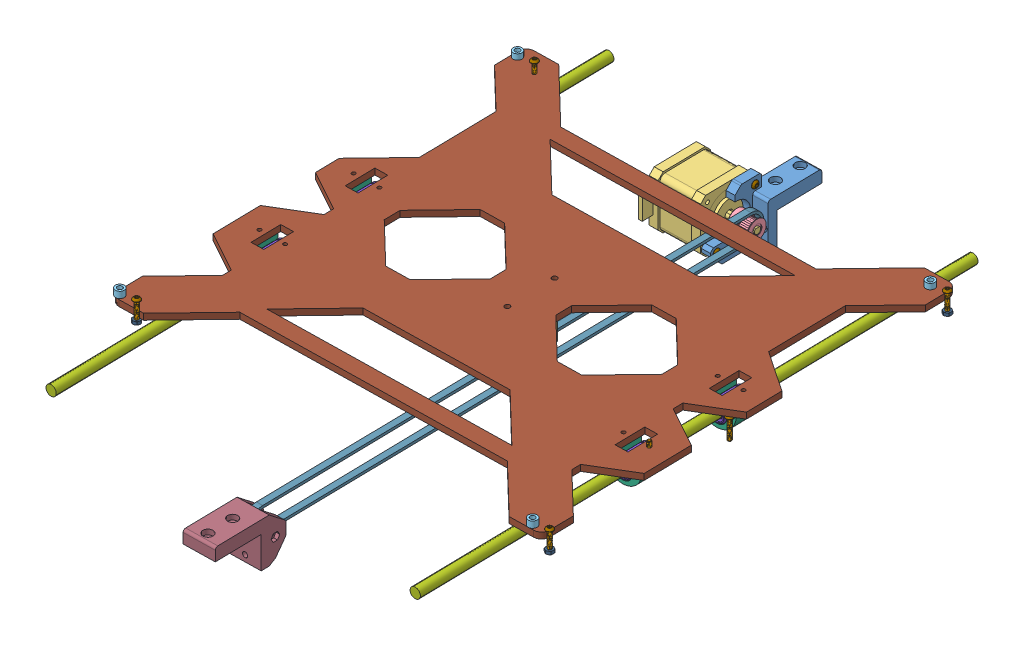
SolidWorks assembly Y Assembly, configuration Default. Lengths in mm.
Overall size (352.33 81 500.19).
42 component instances, 16 part files, 59 mates.
Components (placement in the parent):
- PrintBed_328x328-1: PrintBed_328x328 [Default] at (148.0124 43.9926 305.9077) x (0.999825 0 -0.018712) z (0.018712 0 0.999825) size (328 2 340) (hidden)
- y axis motor holder-1: y axis motor holder [Default] at (-4.3973 -9.082 94.7066) x (0 1 0) z (0.999825 0 -0.018712) size (46.75 77.5 19)
- 624U pillow-1: 624U pillow [Standard] at (74.1469 -91.082 589.2534) x (0 1 0) z (0.018712 0 0.999825) size (13 4 13)
- 40-42 motor-1: 40-42 motor [Standard] at (-45.9053 -85.582 96.0835) x (0 1 0) z (-0.018712 0 -0.999825) size (42 64 50.7)
- 2GT-pulley-2: 2GT-pulley [Standard] at (-58.242 121.3888 274.0832) x (0.999825 0 -0.018712) z (0.018712 0 0.999825) size (16 15 15)
- 5mm Bed Spacer-1: 5mm Bed Spacer [Default] at (-134.2258 34.9926 494.9836) size (7 5 7)
- 5mm Bed Spacer-2: 5mm Bed Spacer [Default] at (186.7203 34.9926 489.0988) size (7 5 7)
- 5mm Bed Spacer-3: 5mm Bed Spacer [Default] at (180.5919 34.398 168.1573) size (7 5 7)
- 5mm Bed Spacer-4: 5mm Bed Spacer [Default] at (-140.2301 34.398 174.1616) size (7 5 7)
- HeatBed 300mm-1: HeatBed 300mm [Default] at (26.2199 39.9926 264.6988) x (0.999825 0 -0.018712) z (0.018712 0 0.999825) size (327 4 327) (hidden)
- Bed Holder-3: Bed Holder [Default] at (-121.7577 30.1666 403.8738) x (0.018712 0 0.999825) z (0.999825 0 -0.018712) size (22 20 30)
- Bed Holder-4: Bed Holder [Default] at (159.7692 30.1666 322.5141) x (0.018712 0 0.999825) z (0.999825 0 -0.018712) size (22 20 30)
- Bed Holder-5: Bed Holder [Default] at (160.7796 30.1666 376.5016) x (-0.018712 0 -0.999825) z (-0.999825 0 0.018712) size (22 20 30)
- Bed Holder-6: Bed Holder [Default] at (-123.593 30.1666 305.8134) x (-0.018712 0 -0.999825) z (-0.999825 0 0.018712) size (22 20 30)
- BedSlider-1: BedSlider [Default] at (160.3516 26.2711 115.9371) x (0.404254 0.914616 -0.007566) z (0.018712 0 0.999825) size (8 8 450)
- BedSlider-2: BedSlider [Default] at (-126.0037 27.7452 121.2964) x (-0.108153 0.994132 0.002024) z (0.018712 0 0.999825) size (8 8 450)
- lm8uu-1: lm8uu [Default] at (159.5633 20.6666 311.516) x (0.999825 0 -0.018712) z (0.018712 0 0.999825) size (15 15 24)
- lm8uu-2: lm8uu [Default] at (160.9854 20.6666 387.4997) x (0.999825 0 -0.018712) z (0.018712 0 0.999825) size (15 15 24)
- lm8uu-3: lm8uu [Default] at (-121.9636 20.6666 392.8757) x (0.999825 0 -0.018712) z (0.018712 0 0.999825) size (15 15 24)
- lm8uu-4: lm8uu [Default] at (-123.3871 20.6666 316.8115) x (0.999825 0 -0.018712) z (0.018712 0 0.999825) size (15 15 24)
- M3X16MM-1: M3X16MM [92095A184] at (190.5681 45.048 170.847) x (0.585178 0 0.810905) z (0 1 0) size (5.7 5.7 18)
- M3X16MM-2: M3X16MM [92095A184] at (-130.3757 45.048 176.8536) x (0.988184 0 0.153271) z (0 1 0) size (5.7 5.7 18)
- M3X16MM-3: M3X16MM [92095A184] at (-124.3691 45.048 497.7974) x (0.998383 0 0.056849) z (0 1 0) size (5.7 5.7 18)
- M3X16MM-4: M3X16MM [92095A184] at (196.5747 45.048 491.7908) x (0.969741 0 0.244134) z (0 1 0) size (5.7 5.7 18)
- M3-1: M3 [90591A250] at (-130.3757 17.3906 176.8536) x (0.962335 0 -0.271866) z (0 1 0) size (5.5 6.35 2.78)
- M3-2: M3 [90591A250] at (190.5681 28.9666 170.847) x (1 0 0) z (0 1 0) size (5.5 6.35 2.78)
- M3-3: M3 [90591A250] at (196.5747 28.9666 491.7908) x (1 0 0) z (0 1 0) size (5.5 6.35 2.78)
- M3-4: M3 [90591A250] at (-124.3691 28.9666 497.7974) x (0.977813 0 0.209477) z (0 -1 0) size (5.5 6.35 2.78)
- M3X16MM-5: M3X16MM [92095A184] at (170.9836 21.7666 387.3126) x (-0.990608 0 0.136731) z (0 -1 0) size (5.7 5.7 18)
- M3X16MM-6: M3X16MM [92095A184] at (150.939 25.0666 399.5855) x (-0.757878 0 0.652397) z (0 1 0) size (5.7 5.7 18)
- M3X16MM-7: M3X16MM [92095A184] at (150.939 25.0666 323.5885) x (-0.527844 0 0.849341) z (0 1 0) size (5.7 5.7 18)
- M3X16MM-8: M3X16MM [92095A184] at (170.939 25.0666 323.5885) x (-0.850892 0 0.525341) z (0 1 0) size (5.7 5.7 18)
- M3X16MM-9: M3X16MM [92095A184] at (-127.261 25.0666 399.5855) x (-0.32634 0 -0.945252) z (0 1 0) size (5.7 5.7 18)
- M3X16MM-10: M3X16MM [92095A184] at (-107.261 25.0666 399.5855) x (-0.992075 0 0.125643) z (0 1 0) size (5.7 5.7 18)
- M3X16MM-11: M3X16MM [92095A184] at (-127.261 25.0666 323.5885) x (-0.951434 0 -0.307853) z (0 1 0) size (5.7 5.7 18)
- M3X16MM-12: M3X16MM [92095A184] at (-107.261 25.871 323.5885) x (-0.671818 0 -0.740717) z (0 1 0) size (5.7 5.7 18)
- M3X16MM-13: M3X16MM [92095A184] at (5.6078 -25.582 167.032) x (-0.018712 0 -0.999825) z (0.999825 0 -0.018712) size (5.7 5.7 18)
- M3X16MM-14: M3X16MM [92095A184] at (5.0277 5.418 136.0374) x (-0.018712 0 -0.999825) z (0.999825 0 -0.018712) size (5.7 5.7 18)
- flatbed-2: flatbed [Default] at (144.4975 32.5796 357.2347) x (0.999825 0 -0.018712) z (0 -1 0) size (335 335 4.83)
- y belt holder-1: y belt holder [Default] at (10.4795 30.1666 328.4691) x (0.999825 0 -0.018712) z (0 -1 0) size (14 52 33.5)
- Y axis Idler Holder-1: Y axis Idler Holder [Default] at (21.7058 0.918 594.3056) x (0.018712 0 0.999825) z (0 -1 0) size (56.89 25 35)
- belt-4: belt [Default] at (16.5258 -7.7421 183.9241) x (0.01871 0.016655 0.999686) z (-0.999825 0 0.018712) size (414.43 26.57 5)
Mates (geometry in assembly coordinates):
- Concentric1: concentric aligned: cylinder of 40-42 motor-1 through (20.665 -10.082 151.2475) axis (-0.999825 0 0.018712) radius 2.5; cylinder of 2GT-pulley-2 through (4.6678 -10.082 151.5469) axis (-0.999825 0 0.018712) radius 2.5
- Distance1: distance = 5.5 mm anti-aligned: plane of 2GT-pulley-2 through (4.1679 -10.082 151.5562) normal (-0.999825 0 0.018712); plane of 40-42 motor-1 through (-1.3311 -10.082 151.6592) normal (0.999825 0 -0.018712)
- Coincident37: coincident anti-aligned: plane of PrintBed_328x328-1 through (148.0124 43.9926 305.9077) normal (0 -1 0); plane of HeatBed 300mm-1 through (26.2199 43.9926 264.6988) normal (0 1 0)
- Coincident38: coincident aligned: plane of PrintBed_328x328-1 through (-152.5991 45.9926 169.1586) normal (-0.018712 0 -0.999825); plane of HeatBed 300mm-1 through (-151.5993 43.9926 169.1399) normal (-0.018712 0 -0.999825)
- Coincident39: coincident aligned: plane of PrintBed_328x328-1 through (175.3434 45.9926 163.021) normal (0.999825 0 -0.018712); plane of HeatBed 300mm-1 through (175.3434 43.9926 163.021) normal (0.999825 0 -0.018712)
- Concentric7: concentric aligned: cylinder of Bed Holder-3 through (-121.7016 20.6666 406.8733) axis (-0.018712 0 -0.999825) radius 7.735; cylinder of BedSlider-2 through (-118.6254 20.6666 571.2371) axis (-0.018712 0 -0.999825) radius 4
- Concentric8: concentric anti-aligned: cylinder of Bed Holder-6 through (-123.6491 20.6666 302.814) axis (0.018712 0 0.999825) radius 7.735; cylinder of BedSlider-2 through (-118.6254 20.6666 571.2371) axis (-0.018712 0 -0.999825) radius 4
- Concentric10: concentric anti-aligned: cylinder of Bed Holder-5 through (160.7234 20.6666 373.5021) axis (0.018712 0 0.999825) radius 7.735; cylinder of BedSlider-1 through (164.325 20.6666 565.9415) axis (-0.018712 0 -0.999825) radius 4
- Concentric11: concentric aligned: cylinder of Bed Holder-4 through (159.8253 20.6666 325.5135) axis (-0.018712 0 -0.999825) radius 7.735; cylinder of BedSlider-1 through (164.325 20.6666 565.9415) axis (-0.018712 0 -0.999825) radius 4
- Concentric16: concentric aligned: cylinder of Bed Holder-3 through (-121.7016 20.6666 406.8733) axis (-0.018712 0 -0.999825) radius 7.735; cylinder of lm8uu-3 through (-121.739 20.6666 404.8736) axis (-0.018712 0 -0.999825) radius 7.5
- Distance18: distance = 1 mm aligned: plane of lm8uu-3 through (-121.739 20.6666 404.8736) normal (0.018712 0 0.999825); plane of Bed Holder-3 through (-136.7551 10.1666 404.1545) normal (0.018712 0 0.999825)
- Concentric17: concentric anti-aligned: cylinder of Bed Holder-6 through (-123.6491 20.6666 302.814) axis (0.018712 0 0.999825) radius 7.735; cylinder of lm8uu-4 through (-123.1626 20.6666 328.8094) axis (-0.018712 0 -0.999825) radius 7.5
- Distance19: distance = 1 mm aligned: plane of lm8uu-4 through (-123.1626 20.6666 328.8094) normal (0.018712 0 0.999825); plane of Bed Holder-6 through (-108.1839 10.1666 327.5289) normal (0.018712 0 0.999825)
- Concentric18: concentric aligned: cylinder of Bed Holder-4 through (159.8253 20.6666 325.5135) axis (-0.018712 0 -0.999825) radius 7.735; cylinder of lm8uu-1 through (159.7879 20.6666 323.5139) axis (-0.018712 0 -0.999825) radius 7.5
- Distance20: distance = 1 mm aligned: plane of lm8uu-1 through (159.3388 20.6666 299.5181) normal (-0.018712 0 -0.999825); plane of Bed Holder-4 through (144.3601 10.1666 300.7986) normal (-0.018712 0 -0.999825)
- Concentric19: concentric anti-aligned: cylinder of Bed Holder-5 through (160.7234 20.6666 373.5021) axis (0.018712 0 0.999825) radius 7.735; cylinder of lm8uu-2 through (161.2099 20.6666 399.4976) axis (-0.018712 0 -0.999825) radius 7.5
- Distance21: distance = 1 mm aligned: plane of lm8uu-2 through (160.7608 20.6666 375.5018) normal (-0.018712 0 -0.999825); plane of Bed Holder-5 through (175.7769 10.1666 376.2209) normal (-0.018712 0 -0.999825)
- Coincident66: coincident aligned: plane of BedSlider-1 through (155.9045 20.6666 116.0203) normal (-0.018712 0 -0.999825); plane of BedSlider-2 through (-127.0459 20.6666 121.3159) normal (-0.018712 0 -0.999825)
- Coincident67: coincident anti-aligned: plane of y axis motor holder-1 through (-4.3973 -9.082 94.7066) normal (-0.999825 0 0.018712); plane of 40-42 motor-1 through (-3.3308 -10.082 151.6966) normal (0.999825 0 -0.018712)
- Concentric30: concentric anti-aligned: circle of M3X16MM-2; circle of M3-1
- Concentric31: concentric anti-aligned: cylinder of M3X16MM-3 through (-124.3691 45.048 497.7974) axis (0 1 0) radius 2.85; circle of M3-4
- Concentric33: concentric anti-aligned: circle of M3X16MM-4; circle of M3-3
- Concentric34: concentric aligned: circle of M3X16MM-1; circle of M3-2
- Concentric36: concentric anti-aligned: circle of Bed Holder-5; circle of M3X16MM-5
- Concentric44: concentric anti-aligned: cylinder of y axis motor holder-1 through (15.3759 5.418 135.8438) axis (-0.999825 0 0.018712) radius 1.625; cylinder of M3X16MM-14 through (5.0277 5.418 136.0374) axis (0.999825 0 -0.018712) radius 2.85
- Concentric45: concentric anti-aligned: cylinder of y axis motor holder-1 through (15.956 -25.582 166.8383) axis (-0.999825 0 0.018712) radius 1.625; circle of M3X16MM-13
- Coincident92: coincident anti-aligned: plane of y axis motor holder-1 through (3.6593 -10.0412 151.0983) normal (0.999825 0 -0.018712); plane of M3X16MM-13 through (3.9581 -28.432 167.0629) normal (-0.999825 0 0.018712)
- Coincident93: coincident anti-aligned: plane of y axis motor holder-1 through (3.6593 -10.0412 151.0983) normal (0.999825 0 -0.018712); plane of M3X16MM-14 through (3.378 2.568 136.0683) normal (-0.999825 0 0.018712)
- Concentric47: concentric aligned: cylinder of 40-42 motor-1 through (-8.0398 -25.582 167.2874) axis (0.999825 0 -0.018712) radius 1.5; circle of M3X16MM-13
- Concentric48: concentric aligned: cylinder of 40-42 motor-1 through (-8.6199 5.418 136.2929) axis (0.999825 0 -0.018712) radius 1.5; circle of M3X16MM-14
- Coincident97: coincident anti-aligned: plane of 5mm Bed Spacer-2 through (178.4067 34.9926 487.0204) normal (0 -1 0); plane of flatbed-2 through (144.4975 34.9926 357.2347) normal (0 1 0)
- Concentric50: concentric anti-aligned: cylinder of 5mm Bed Spacer-3 through (172.2783 39.398 166.0789) axis (0 -1 0) radius 2; cylinder of flatbed-2 through (172.2783 30.1666 166.0789) axis (0 1 0) radius 1.4605
- Concentric51: concentric anti-aligned: cylinder of 5mm Bed Spacer-1 through (-142.5394 39.9926 492.9052) axis (0 -1 0) radius 2; cylinder of flatbed-2 through (-142.5394 30.1666 492.9052) axis (0 1 0) radius 1.4605
- Coincident98: coincident anti-aligned: circle of 5mm Bed Spacer-1; plane of HeatBed 300mm-1 through (26.2199 39.9926 264.6988) normal (0 -1 0)
- Coincident99: coincident anti-aligned: plane of 5mm Bed Spacer-1 through (-142.5394 34.9926 492.9052) normal (0 -1 0); plane of flatbed-2 through (144.4975 34.9926 357.2347) normal (0 1 0)
- Concentric52: concentric aligned: cylinder of 5mm Bed Spacer-4 through (-148.5437 39.398 172.0832) axis (0 -1 0) radius 2; circle of flatbed-2
- Coincident101: coincident anti-aligned: plane of M3-2 through (187.8181 30.1666 169.2593) normal (0 1 0); plane of flatbed-2 through (144.4975 30.1666 357.2347) normal (0 -1 0)
- Coincident102: coincident anti-aligned: plane of M3-3 through (193.8247 30.1666 490.2031) normal (0 1 0); plane of flatbed-2 through (144.4975 30.1666 357.2347) normal (0 -1 0)
- Coincident103: coincident anti-aligned: plane of M3-4 through (-127.3907 30.1666 498.7738) normal (0 1 0); plane of flatbed-2 through (144.4975 30.1666 357.2347) normal (0 -1 0)
- Coincident104: coincident anti-aligned: plane of flatbed-2 through (144.4975 30.1666 357.2347) normal (0 -1 0); plane of y belt holder-1 through (10.966 30.1666 354.4646) normal (0 1 0)
- Concentric53: concentric anti-aligned: cylinder of flatbed-2 through (17.9966 30.1666 309.2751) axis (0 1 0) radius 2; cylinder of y belt holder-1 through (17.9966 19.1666 309.2751) axis (0 -1 0) radius 3.5
- Concentric54: concentric anti-aligned: cylinder of flatbed-2 through (18.7095 30.1666 347.3684) axis (0 1 0) radius 2; cylinder of y belt holder-1 through (18.7095 19.1666 347.3684) axis (0 -1 0) radius 3.75
- Coincident108: coincident anti-aligned: plane of Bed Holder-6 through (-123.593 30.1666 305.8134) normal (0 1 0); plane of flatbed-2 through (144.4975 30.1666 357.2347) normal (0 -1 0)
- Concentric56: concentric anti-aligned: circle of Bed Holder-5; circle of flatbed-2
- Concentric57: concentric aligned: circle of Bed Holder-4; circle of flatbed-2
- Concentric66: concentric anti-aligned: circle of HeatBed 300mm-1; circle of flatbed-2
- Concentric67: concentric aligned: circle of 5mm Bed Spacer-2; circle of HeatBed 300mm-1
- Distance22: distance = 3 mm anti-aligned: plane of 624U pillow-1 through (22.931 -7.582 552.8871) normal (0.999825 0 -0.018712); plane of Y axis Idler Holder-1 through (25.8909 0.918 550.7197) normal (-0.999825 0 0.018712)
- Concentric68: concentric aligned: circle of 624U pillow-1; circle of Y axis Idler Holder-1
- Distance25: distance = 500 mm anti-aligned: plane of Y axis Idler Holder-1 through (9.208 -9.082 594.5395) normal (0.018712 0 0.999825); plane of y axis motor holder-1 through (14.5993 -9.082 94.351) normal (-0.018712 0 -0.999825)
- Distance37: distance = 0.5 mm aligned: plane of 624U pillow-1 through (22.931 -7.582 552.8871) normal (0.999825 0 -0.018712); plane of belt-4 through (23.2974 -10.082 545.7474) normal (0.999825 0 -0.018712)
- Concentric70: concentric aligned: circle of 2GT-pulley-2; circle of belt-4
- Coincident109: coincident aligned: plane of y axis motor holder-1 through (15.273 -9.082 130.3447) normal (0 -1 0); plane of Y axis Idler Holder-1 through (8.5156 -9.082 557.546) normal (0 -1 0)
- Concentric74: concentric anti-aligned: circle of Bed Holder-6; circle of flatbed-2
- Distance43: distance = 3 mm anti-aligned: plane of y belt holder-1 through (20.7584 2.9166 343.2794) normal (0 -1 0); plane of belt-4 through (10.9199 -0.0834 151.5965) normal (0 1 0)
- Distance41: distance = 1.75 mm aligned: plane of y belt holder-1 through (12.7598 -3.3334 343.4291) normal (-0.999825 0 0.018712); plane of belt-4 through (18.2983 -10.082 545.8409) normal (-0.999825 0 0.018712)
- Distance42: distance = 240 mm aligned: plane of y belt holder-1 through (10.966 30.1666 354.4646) normal (0.018712 0 0.999825); plane of Y axis Idler Holder-1 through (9.208 -9.082 594.5395) normal (0.018712 0 0.999825)
- Coincident121: coincident anti-aligned: plane of Bed Holder-4 through (159.7692 30.1666 322.5141) normal (0 1 0); plane of flatbed-2 through (144.4975 30.1666 357.2347) normal (0 -1 0)
- Distance47: distance = 5.5 mm aligned: plane of y belt holder-1 through (24.9635 30.1666 354.2026) normal (0.999825 0 -0.018712); plane of y axis motor holder-1 through (14.5993 -9.082 94.351) normal (0.999825 0 -0.018712)
